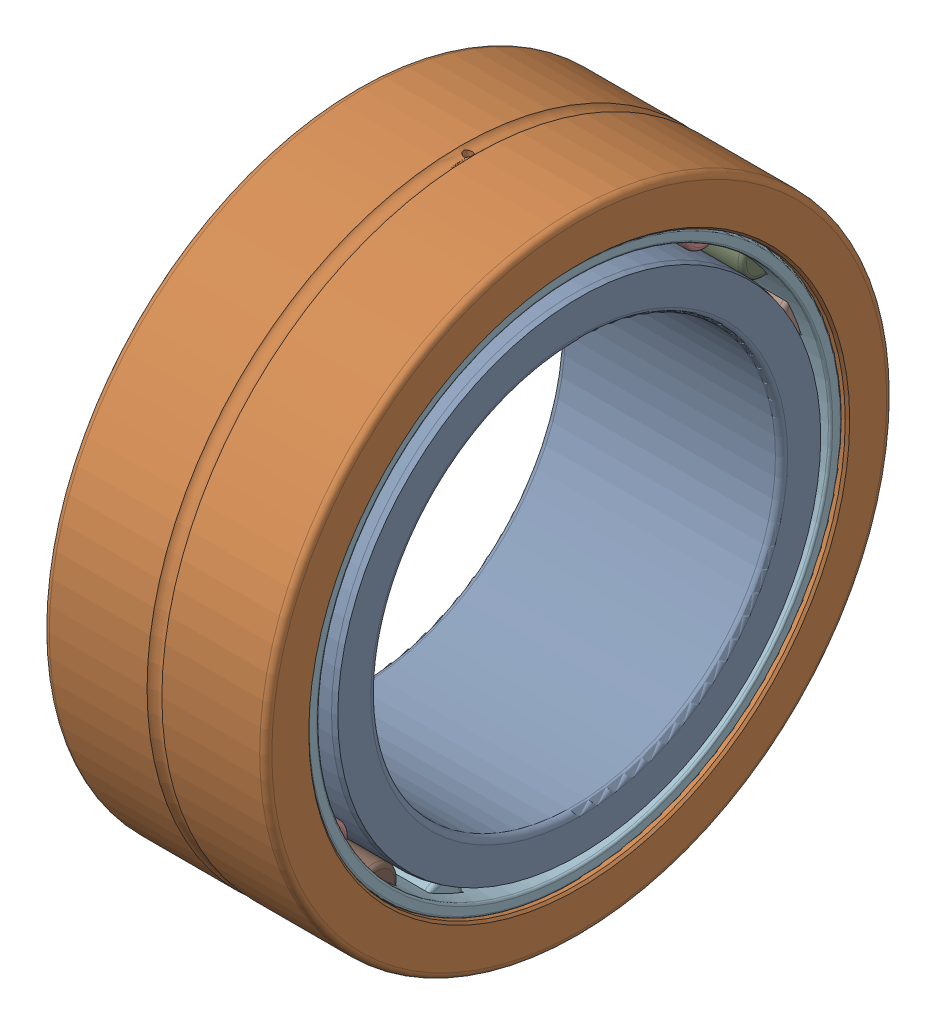
SolidWorks assembly NA4908R, configuration Default. Lengths in mm.
Overall size (22 62 62).
24 component instances, 4 part files, 0 mates.
Components (placement in the parent):
- NA4908RInner ring-1: NA4908RInner ring [Default] at origin size (22 48 48)
- NA4908ROuter ring-1: NA4908ROuter ring [Default] at origin size (22 62 62)
- NA4908R ring-1: NA4908R ring [Default] at (2.2 26.1 0) size (17.6 4.2 4.2)
- NA4908R ring-2: NA4908R ring [Default] at (2.2 24.9405 7.6931) size (17.6 4.2 4.2)
- NA4908R ring-3: NA4908R ring [Default] at (2.2 21.5648 14.7027) size (17.6 4.2 4.2)
- NA4908R ring-4: NA4908R ring [Default] at (2.2 16.2731 20.4058) size (17.6 4.2 4.2)
- NA4908R ring-5: NA4908R ring [Default] at (2.2 9.5354 24.2958) size (17.6 4.2 4.2)
- NA4908R ring-6: NA4908R ring [Default] at (2.2 1.9505 26.027) size (17.6 4.2 4.2)
- NA4908R ring-7: NA4908R ring [Default] at (2.2 -5.8078 25.4456) size (17.6 4.2 4.2)
- NA4908R ring-8: NA4908R ring [Default] at (2.2 -13.05 22.6033) size (17.6 4.2 4.2)
- NA4908R ring-9: NA4908R ring [Default] at (2.2 -19.1327 17.7525) size (17.6 4.2 4.2)
- NA4908R ring-10: NA4908R ring [Default] at (2.2 -23.5153 11.3244) size (17.6 4.2 4.2)
- NA4908R ring-11: NA4908R ring [Default] at (2.2 -25.8085 3.89) size (17.6 4.2 4.2)
- NA4908R ring-12: NA4908R ring [Default] at (2.2 -25.8085 -3.89) size (17.6 4.2 4.2)
- NA4908R ring-13: NA4908R ring [Default] at (2.2 -23.5153 -11.3244) size (17.6 4.2 4.2)
- NA4908R ring-14: NA4908R ring [Default] at (2.2 -19.1327 -17.7525) size (17.6 4.2 4.2)
- NA4908R ring-15: NA4908R ring [Default] at (2.2 -13.05 -22.6033) size (17.6 4.2 4.2)
- NA4908R ring-16: NA4908R ring [Default] at (2.2 -5.8078 -25.4456) size (17.6 4.2 4.2)
- NA4908R ring-17: NA4908R ring [Default] at (2.2 1.9505 -26.027) size (17.6 4.2 4.2)
- NA4908R ring-18: NA4908R ring [Default] at (2.2 9.5354 -24.2958) size (17.6 4.2 4.2)
- NA4908R ring-19: NA4908R ring [Default] at (2.2 16.2731 -20.4058) size (17.6 4.2 4.2)
- NA4908R ring-20: NA4908R ring [Default] at (2.2 21.5648 -14.7027) size (17.6 4.2 4.2)
- NA4908R ring-21: NA4908R ring [Default] at (2.2 24.9405 -7.6931) size (17.6 4.2 4.2)
- NA4908RCage-1: NA4908RCage [Default] at origin size (21.12 52.94 52.94)
